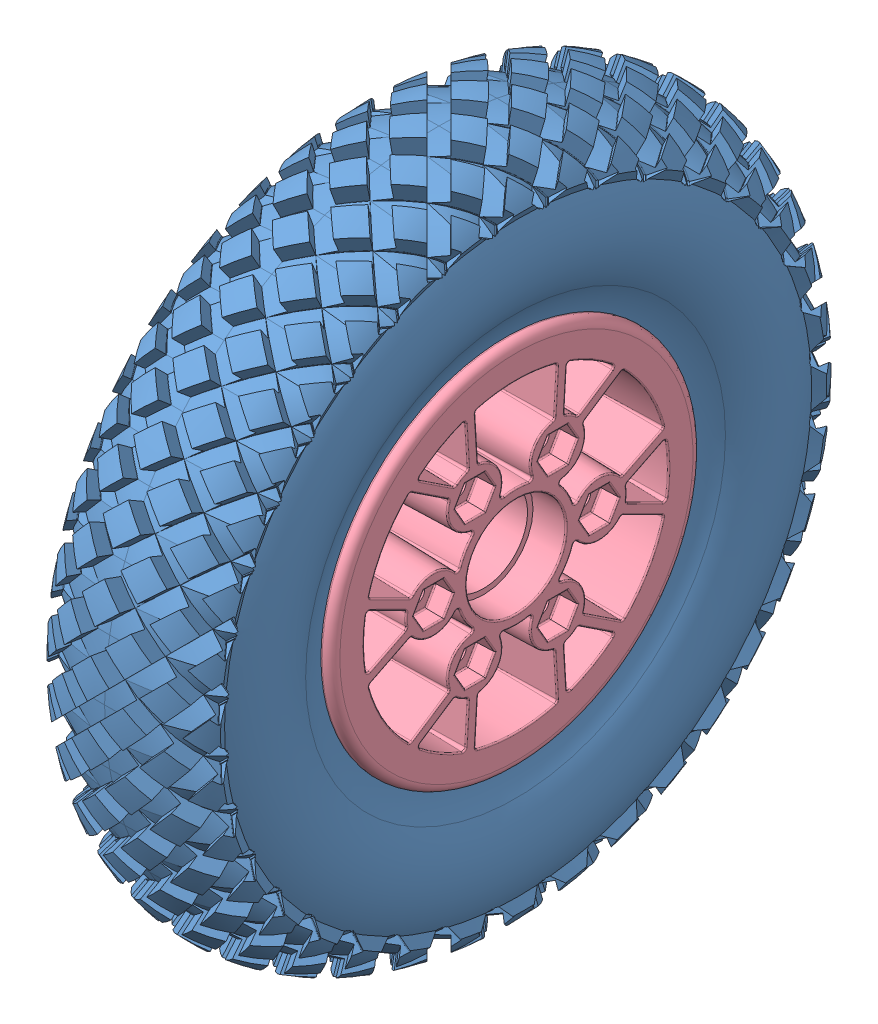
SolidWorks assembly Pneumatic Wheel, configuration Default. Lengths in mm.
Overall size (54.46 203.4 203.4).
11 component instances, 4 part files, 0 mates.
Components (placement in the parent):
- Tire-1: Tire [Default] at (-14.0642 3.9407 4.9955) x (0 0 1) z (-1 0 0) size (203.4 203.4 50.81)
- Valve-1: Valve [Default] at (-14.5404 48.2951 4.9955) x (0 1 0) z (0 0 1) size (16.51 34.98 12.8)
- Pneumatic Hub-1: Pneumatic Hub [Default] at (-8.6594 5.0758 -4.0835) size (45.47 106.55 106.55)
  - #4x1.00, Plastic Thread Rolling Screw, Pan Head, Cross Recessed, Zinc Plated (Plastic Applications)_-1: #4x1.00, Plastic Thread Rolling Screw, Pan Head, Cross Recessed, Zinc Plated (Plastic Applications)_ [Default] at (7.3269 34.0601 29.3991) x (-1 0 0) z (0 -0.924225 -0.381849) size (27.43 5.56 5.56)
  - Hub-1: Hub [Default] at (-28.6141 -1.1351 9.0791) size (25.79 106.55 106.55)
  - #4x1.00, Plastic Thread Rolling Screw, Pan Head, Cross Recessed, Zinc Plated (Plastic Applications)_-2: #4x1.00, Plastic Thread Rolling Screw, Pan Head, Cross Recessed, Zinc Plated (Plastic Applications)_ [Default] at (7.3269 -1.1351 -31.5609) x (-1 0 0) z (0 0.131421 0.991327) size (27.43 5.56 5.56)
  - #4x1.00, Plastic Thread Rolling Screw, Pan Head, Cross Recessed, Zinc Plated (Plastic Applications)_-3: #4x1.00, Plastic Thread Rolling Screw, Pan Head, Cross Recessed, Zinc Plated (Plastic Applications)_ [Default] at (-19.0891 -1.1351 49.7191) x (1 0 0) z (0 -0.750107 0.661316) size (27.43 5.56 5.56)
  - #4x1.00, Plastic Thread Rolling Screw, Pan Head, Cross Recessed, Zinc Plated (Plastic Applications)_-4: #4x1.00, Plastic Thread Rolling Screw, Pan Head, Cross Recessed, Zinc Plated (Plastic Applications)_ [Default] at (7.3269 -36.3304 29.3991) x (-1 0 0) z (0 0.792804 -0.609477) size (27.43 5.56 5.56)
  - #4x1.00, Plastic Thread Rolling Screw, Pan Head, Cross Recessed, Zinc Plated (Plastic Applications)_-5: #4x1.00, Plastic Thread Rolling Screw, Pan Head, Cross Recessed, Zinc Plated (Plastic Applications)_ [Default] at (-19.0891 34.0601 -11.2409) x (1 0 0) z (0 0.94777 0.318954) size (27.43 5.56 5.56)
  - #4x1.00, Plastic Thread Rolling Screw, Pan Head, Cross Recessed, Zinc Plated (Plastic Applications)_-6: #4x1.00, Plastic Thread Rolling Screw, Pan Head, Cross Recessed, Zinc Plated (Plastic Applications)_ [Default] at (-19.0891 -36.3304 -11.2409) x (1 0 0) z (0 -0.197663 -0.98027) size (27.43 5.56 5.56)
  - Hub-2: Hub [Default] at (16.8519 -1.1351 9.0791) x (-1 0 0) z (0 0 -1) size (25.79 106.55 106.55)
